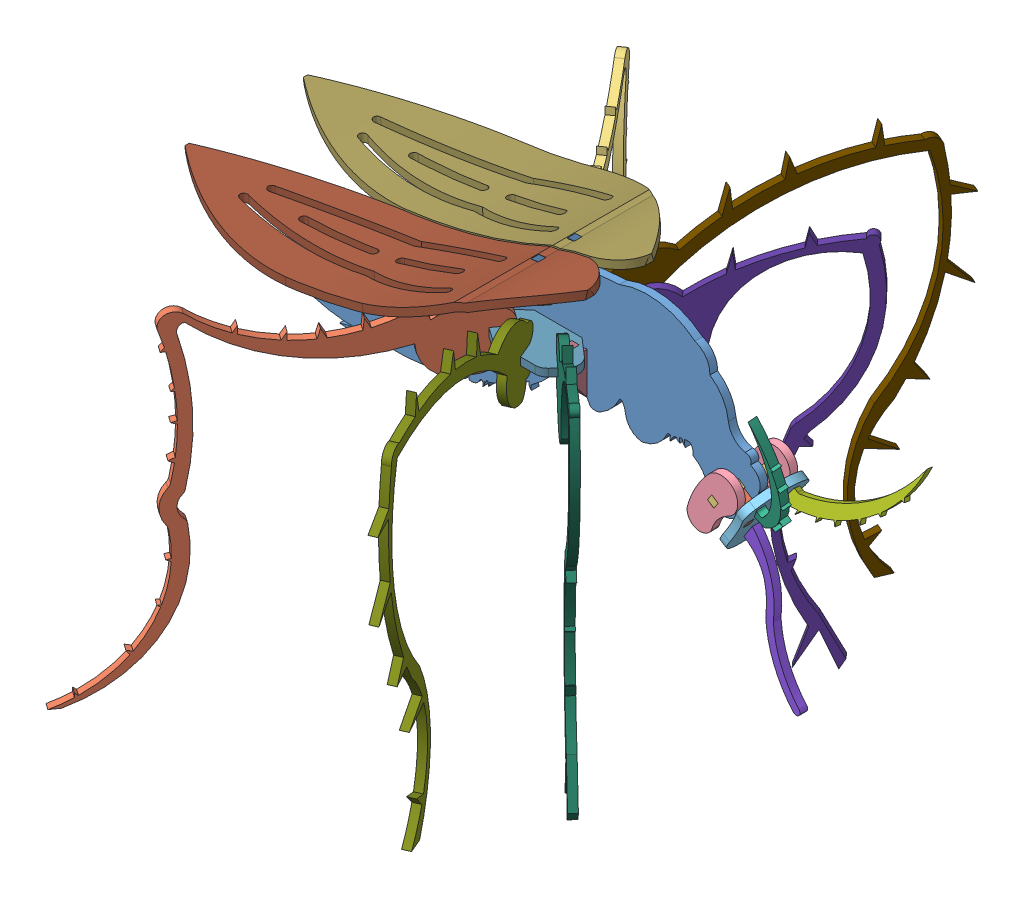
SolidWorks assembly _Assy, Mosquito Rev 0, configuration Default. Lengths in mm.
Overall size (127.53 78.08 120.97).
24 component instances, 21 part files, 68 mates.
Components (placement in the parent):
- Mosquito, Profile-1: Mosquito, Profile [Default] at (-40.9483 -56.761 -14.7323) size (93.14 36.88 1.52)
- Mosquito, Face Plt, Connector-1: Mosquito, Face Plt, Connector [Default] at (15.6801 29.1957 -14.7323) x (0.835069 -0.550145 0) z (0.550145 0.835069 0) size (6.57 8.05 1.52)
- Mosquito, Eye Plt, Connector-1: Mosquito, Eye Plt, Connector [Default] at (62.8149 -1.8568 -14.7323) x (0.550145 0.835069 0) z (-0.835069 0.550145 0) size (2.82 5.2 1.52)
- Mosquito, Eye Plt, Connector-2: Mosquito, Eye Plt, Connector [Default] at (61.5423 -1.0184 -13.2083) x (0.550145 0.835069 0) z (0.835069 -0.550145 0) size (2.82 5.2 1.52)
- Mosquito, Eye-1: Mosquito, Eye [Default] at (61.5423 -1.0184 -9.5093) x (0.550145 0.835069 0) z (0 0 1) size (13.17 6.9 1.52)
- Mosquito, Eye-2: Mosquito, Eye [Default] at (61.5423 -1.0184 -19.9552) x (0.550145 0.835069 0) z (0 0 1) size (13.17 6.9 1.52)
- Mosquito, Face-1: Mosquito, Face [Default] at (66.6075 -4.3553 -14.7323) x (-0.550145 -0.835069 0) z (0.835069 -0.550145 0) size (16.76 12.6 1.52)
- Mosquito, Face Antenna - 01-1: Mosquito, Face Antenna - 01 [Default] at (66.3759 -4.7068 -13.6923) x (0.509952 0.774061 0.375204) z (-0.206417 -0.313322 0.926942) size (30.63 11.64 1.52)
- Mosquito, Face Antenna - 02-1: Mosquito, Face Antenna - 02 [Default] at (66.6675 -4.2642 -14.4628) x (-0.509952 -0.774061 0.375204) z (-0.206417 -0.313322 -0.926942) size (22.51 13.81 1.52)
- Mosquito, Face, Biter-1: Mosquito, Face, Biter [Default] at (66.6075 -4.3553 -13.2083) x (-0.550145 -0.835069 0) z (0 0 -1) size (18.96 24.73 1.52)
- Mosquito, Wing Plt, Connector-1: Mosquito, Wing Plt, Connector [Default] at (-47.8002 6.962 -14.7323) x (0.994269 0.106911 0) z (-0.106911 0.994269 0) size (9.72 13.37 1.52)
- Mosquito, Wing Plt-1: Mosquito, Wing Plt [Default] at (-47.8002 6.962 -11.1106) x (-0.994269 -0.106911 0) z (0 0 1) size (6.76 6.62 1.52)
- Mosquito, Wing Plt-2: Mosquito, Wing Plt [Default] at (-47.8002 6.962 -18.3539) x (-0.994269 -0.106911 0) z (0 0 1) size (6.76 6.62 1.52)
- Mosquito, Wing-1: Mosquito, Wing [Default] at (-47.8002 6.962 -9.5866) x (-0.994269 -0.106911 0) z (0 0 1) size (75.96 9.36 29.29)
- MirrorMosquito, Wing-2: MirrorMosquito, Wing [Default] at (-47.8002 6.962 -18.3539) x (-0.994269 -0.106911 0) z (0 0 1) size (75.96 9.36 29.29)
- Mosquito, Leg Plt, Connector-1: Mosquito, Leg Plt, Connector [Default] at (32.2496 -56.761 -14.7323) x (0 0 1) z (-1 0 0) size (13.29 9.8 1.52)
- Mosquito, Leg Plt, Base-1: Mosquito, Leg Plt, Base [Default] at (32.2496 7.7234 -14.7323) x (0 0 1) z (0 1 0) size (9.45 17.8 1.52)
- Mosquito, Leg, Front-1: Mosquito, Leg, Front [Default] at (29.5385 7.7234 -11.7482) x (0 -1 0) z (-0.672441 0 0.740151) size (75.29 39.25 1.52)
- Mosquito, Leg, Middle-1: Mosquito, Leg, Middle [Default] at (24.4896 7.7234 -13.0681) x (-0.39243 0 -0.919782) z (-0.919782 0 0.39243) size (58.76 78.08 1.52)
- MirrorMosquito, Leg, Front-2: MirrorMosquito, Leg, Front [Default] at (29.5385 7.7234 -16.1923) x (0 -1 0) z (0.672441 0 0.740151) size (75.29 39.25 1.52)
- MirrorPart4^_Assy, Mosquito Rev 0-3: MirrorPart4^_Assy, Mosquito Rev 0 [Default] at (24.4896 7.7234 -14.8724) x (-0.39243 0 0.919782) z (0.919782 0 0.39243) size (58.76 78.08 1.52) (virtual)
- MirrorMosquito, Leg Plt, Base-2: MirrorMosquito, Leg Plt, Base [Default] at (32.2496 7.7234 -13.2083) x (0 0 -1) z (0 -1 0) size (9.45 17.8 1.52)
- Mosquito, Leg, Rear-1: Mosquito, Leg, Rear [Default] at (27.2529 7.7234 -18.2575) x (-0.576476 0 0.817114) z (0.817114 0 0.576476) size (67.19 66.57 1.52)
- MirrorMosquito, Leg, Rear-2: MirrorMosquito, Leg, Rear [Default] at (27.2529 7.7234 -9.6831) x (-0.576476 0 -0.817114) z (-0.817114 0 0.576476) size (67.19 66.57 1.52)
Mates (geometry in assembly coordinates):
- InPlace2: in place: plane of Mosquito, Profile-1 through (15.6801 29.1957 -14.7323) normal (0.550145 0.835069 0); plane of ? through (18.1585 27.5629 0) normal (0.550145 0.835069 0); moOrthogonalPlaneRef_w of Mosquito, Profile-1 through (15.6801 29.1957 -14.7323) normal (0.550145 0.835069 0); unknown of ?; plane of Mosquito, Profile-1 through (15.6801 29.1957 -14.7323) normal (0.550145 0.835069 0); line of ? through (-55 18.1585 27.5629) axis (0 0.835069 -0.550145); plane of Mosquito, Profile-1 through (15.6801 29.1957 -14.7323) normal (0.550145 0.835069 0); unknown of Mosquito, Face Plt, Connector-1
- Coincident4: coincident aligned: plane of Mosquito, Profile-1; plane of Mosquito, Face Plt, Connector-1
- Coincident5: coincident aligned: moOrthogonalPlaneRef_w of Mosquito, Profile-1 through (15.6801 29.1957 -14.7323) normal (0 0 -1); plane of Mosquito, Face Plt, Connector-1
- Coincident6: coincident anti-aligned: moOrthogonalPlaneRef_w of Mosquito, Profile-1 through (15.6801 29.1957 -14.7323) normal (-0.835069 0.550145 0); plane of Mosquito, Face Plt, Connector-1
- InPlace3: in place: plane of Mosquito, Face Plt, Connector-1 through (62.8149 -1.8568 -15.0636) normal (-0.835069 0.550145 0); plane of ? through (44.6564 -29.4197 0) normal (-0.835069 0.550145 0); plane of Mosquito, Face Plt, Connector-1 through (62.8149 -1.8568 -15.0636) normal (-0.835069 0.550145 0); line of ? through (-55 44.6564 -29.4197) axis (0 0.550145 0.835069); plane of Mosquito, Face Plt, Connector-1 through (62.8149 -1.8568 -15.0636) normal (-0.835069 0.550145 0); unknown of ?; plane of Mosquito, Face Plt, Connector-1 through (62.8149 -1.8568 -15.0636) normal (-0.835069 0.550145 0); unknown of Mosquito, Eye Plt, Connector-1
- Coincident7: coincident aligned: plane of Mosquito, Face Plt, Connector-1; plane of Mosquito, Eye Plt, Connector-1
- Coincident8: coincident aligned: moOrthogonalPlaneRef_w of Mosquito, Face Plt, Connector-1 through (62.8149 -1.8568 -14.7323) normal (0 0 -1); plane of Mosquito, Eye Plt, Connector-1
- Coincident9: coincident anti-aligned: moOrthogonalPlaneRef_w of Mosquito, Face Plt, Connector-1 through (62.8149 -1.8568 -14.7323) normal (-0.550145 -0.835069 0); plane of Mosquito, Eye Plt, Connector-1
- Coincident10: coincident anti-aligned: plane of Mosquito, Face Plt, Connector-1 through (15.6801 29.1957 -12.8769) normal (0 0 1); plane of Mosquito, Eye Plt, Connector-2 through (62.8149 -1.8568 -12.8769) normal (0 0 -1)
- Coincident11: coincident anti-aligned: plane of Mosquito, Face Plt, Connector-1 through (62.8149 -1.8568 -12.8769) normal (-0.835069 0.550145 0); plane of Mosquito, Eye Plt, Connector-2 through (62.8149 -1.8568 -13.2083) normal (0.835069 -0.550145 0)
- Coincident12: coincident anti-aligned: plane of Mosquito, Face Plt, Connector-1 through (15.6801 29.1957 -14.7323) normal (-0.550145 -0.835069 0); plane of Mosquito, Eye Plt, Connector-2 through (62.8149 -1.8568 -13.2083) normal (0.550145 0.835069 0)
- InPlace4: in place: plane of Mosquito, Eye Plt, Connector-2 through (62.8149 -1.8568 -9.5093) normal (0 0 1); plane of ? through (0 0 -9.5093) normal (0 0 1); plane of Mosquito, Eye Plt, Connector-2 through (62.8149 -1.8568 -9.5093) normal (0 0 1); plane of ? through (0 0 -9.5093) normal (0 1 0); plane of Mosquito, Eye Plt, Connector-2 through (62.8149 -1.8568 -9.5093) normal (0 0 1); plane of ? through (0 0 -9.5093) normal (1 0 0); plane of Mosquito, Eye Plt, Connector-2 through (62.8149 -1.8568 -9.5093) normal (0 0 1); unknown of Mosquito, Eye-1
- Coincident13: coincident aligned: plane of Mosquito, Eye Plt, Connector-2; plane of Mosquito, Eye-1
- Coincident14: coincident aligned: moOrthogonalPlaneRef_w of Mosquito, Eye Plt, Connector-2 through (61.5423 -1.0184 -9.5093) normal (-0.835069 0.550145 0); plane of Mosquito, Eye-1
- Coincident15: coincident anti-aligned: moOrthogonalPlaneRef_w of Mosquito, Eye Plt, Connector-2 through (61.5423 -1.0184 -9.5093) normal (-0.550145 -0.835069 0); plane of Mosquito, Eye-1
- Coincident16: coincident anti-aligned: plane of Mosquito, Eye Plt, Connector-1 through (61.5423 -1.0184 -18.4312) normal (0 0 -1); plane of Mosquito, Eye-2 through (66.3052 -3.0819 -18.4312) normal (0 0 1)
- Coincident17: coincident anti-aligned: plane of Mosquito, Eye Plt, Connector-1 through (61.5423 -1.0184 -14.7323) normal (-0.550145 -0.835069 0); plane of Mosquito, Eye-2 through (62.8149 -1.8568 -18.4312) normal (0.550145 0.835069 0)
- Coincident18: coincident anti-aligned: plane of Mosquito, Eye Plt, Connector-1 through (62.8149 -1.8568 -14.7323) normal (0.835069 -0.550145 0); plane of Mosquito, Eye-2 through (63.6534 -0.5841 -18.4312) normal (-0.835069 0.550145 0)
- InPlace5: in place: plane of Mosquito, Face Plt, Connector-1 through (67.4459 -3.0826 -9.9445) normal (0.835069 -0.550145 0); plane of ? through (48.449 -31.9182 0) normal (0.835069 -0.550145 0); plane of Mosquito, Face Plt, Connector-1 through (67.4459 -3.0826 -9.9445) normal (0.835069 -0.550145 0); line of ? through (-55 48.449 -31.9182) axis (0 0.550145 0.835069); plane of Mosquito, Face Plt, Connector-1 through (67.4459 -3.0826 -9.9445) normal (0.835069 -0.550145 0); unknown of ?; plane of Mosquito, Face Plt, Connector-1 through (67.4459 -3.0826 -9.9445) normal (0.835069 -0.550145 0); unknown of Mosquito, Face-1
- Coincident19: coincident aligned: plane of Mosquito, Face Plt, Connector-1; plane of Mosquito, Face-1
- Coincident20: coincident aligned: moOrthogonalPlaneRef_w of Mosquito, Face Plt, Connector-1 through (66.6075 -4.3553 -14.7323) normal (0 0 -1); plane of Mosquito, Face-1
- Coincident21: coincident anti-aligned: moOrthogonalPlaneRef_w of Mosquito, Face Plt, Connector-1 through (66.6075 -4.3553 -14.7323) normal (0.550145 0.835069 0); plane of Mosquito, Face-1
- InPlace6: in place: plane of Mosquito, Face-1 through (67.6068 -0.0682 -11.8502) normal (-0.206417 -0.313322 0.926942); plane of ? through (5.1435 7.8074 -23.0978) normal (-0.206417 -0.313322 0.926942); plane of Mosquito, Face-1 through (67.6068 -0.0682 -11.8502) normal (-0.206417 -0.313322 0.926942); unknown of ?; plane of Mosquito, Face-1 through (67.6068 -0.0682 -11.8502) normal (-0.206417 -0.313322 0.926942); unknown of ?; plane of Mosquito, Face-1 through (67.6068 -0.0682 -11.8502) normal (-0.206417 -0.313322 0.926942); unknown of Mosquito, Face Antenna - 01-1
- Coincident22: coincident aligned: plane of Mosquito, Face-1; plane of Mosquito, Face Antenna - 01-1
- Coincident23: coincident aligned: moOrthogonalPlaneRef_w of Mosquito, Face-1 through (66.3759 -4.7068 -13.6923) normal (-0.835069 0.550145 0); plane of Mosquito, Face Antenna - 01-1
- Coincident24: coincident anti-aligned: moOrthogonalPlaneRef_w of Mosquito, Face-1 through (66.3759 -4.7068 -13.6923) normal (-0.509952 -0.774061 -0.375204); plane of Mosquito, Face Antenna - 01-1
- InPlace7: in place: plane of Mosquito, Face-1 through (67.6068 -0.0682 -16.0903) normal (-0.206417 -0.313322 -0.926942); plane of ? through (-0.2025 -0.3074 -0.9093) normal (-0.206417 -0.313322 -0.926942); plane of Mosquito, Face-1 through (67.6068 -0.0682 -16.0903) normal (-0.206417 -0.313322 -0.926942); unknown of ?; plane of Mosquito, Face-1 through (67.6068 -0.0682 -16.0903) normal (-0.206417 -0.313322 -0.926942); unknown of ?; plane of Mosquito, Face-1 through (67.6068 -0.0682 -16.0903) normal (-0.206417 -0.313322 -0.926942); unknown of Mosquito, Face Antenna - 02-1
- Coincident25: coincident aligned: plane of Mosquito, Face-1; plane of Mosquito, Face Antenna - 02-1
- Coincident26: coincident aligned: moOrthogonalPlaneRef_w of Mosquito, Face-1 through (66.6675 -4.2642 -14.4628) normal (-0.835069 0.550145 0); plane of Mosquito, Face Antenna - 02-1
- Coincident27: coincident anti-aligned: moOrthogonalPlaneRef_w of Mosquito, Face-1 through (66.6675 -4.2642 -14.4628) normal (0.509952 0.774061 -0.375204); plane of Mosquito, Face Antenna - 02-1
- InPlace8: in place: plane of Mosquito, Face-1 through (63.5713 -6.1937 -13.2083) normal (0 0 -1); plane of ? through (0 0 -13.2083) normal (0 0 -1); plane of Mosquito, Face-1 through (63.5713 -6.1937 -13.2083) normal (0 0 -1); unknown of ?; plane of Mosquito, Face-1 through (63.5713 -6.1937 -13.2083) normal (0 0 -1); plane of ? through (0 0 -13.2083) normal (-1 0 0); plane of Mosquito, Face-1 through (63.5713 -6.1937 -13.2083) normal (0 0 -1); unknown of Mosquito, Face, Biter-1
- Coincident28: coincident aligned: plane of Mosquito, Face-1; plane of Mosquito, Face, Biter-1
- Coincident29: coincident aligned: moOrthogonalPlaneRef_w of Mosquito, Face-1 through (66.6075 -4.3553 -13.2083) normal (-0.835069 0.550145 0); plane of Mosquito, Face, Biter-1
- Coincident30: coincident anti-aligned: moOrthogonalPlaneRef_w of Mosquito, Face-1 through (66.6075 -4.3553 -13.2083) normal (0.550145 0.835069 0); plane of Mosquito, Face, Biter-1
- InPlace9: in place: plane of Mosquito, Profile-1 through (11.8017 13.3708 -13.2083) normal (-0.106911 0.994269 0); plane of ? through (-1.2864 11.9635 0) normal (-0.106911 0.994269 0); plane of Mosquito, Profile-1 through (11.8017 13.3708 -13.2083) normal (-0.106911 0.994269 0); unknown of ?; plane of Mosquito, Profile-1 through (11.8017 13.3708 -13.2083) normal (-0.106911 0.994269 0); line of ? through (-55 -1.2864 11.9635) axis (0 0.994269 0.106911); plane of Mosquito, Profile-1 through (11.8017 13.3708 -13.2083) normal (-0.106911 0.994269 0); unknown of Mosquito, Wing Plt, Connector-1
- Coincident31: coincident aligned: plane of Mosquito, Profile-1; plane of Mosquito, Wing Plt, Connector-1
- Coincident32: coincident aligned: moOrthogonalPlaneRef_w of Mosquito, Profile-1 through (-47.8002 6.962 -14.7323) normal (0 0 -1); plane of Mosquito, Wing Plt, Connector-1
- Coincident33: coincident anti-aligned: moOrthogonalPlaneRef_w of Mosquito, Profile-1 through (-47.8002 6.962 -14.7323) normal (-0.994269 -0.106911 0); plane of Mosquito, Wing Plt, Connector-1
- InPlace10: in place: plane of Mosquito, Wing Plt, Connector-1 through (26.7529 16.5112 -11.1106) normal (0 0 1); plane of ? through (0 0 -11.1106) normal (0 0 1); plane of Mosquito, Wing Plt, Connector-1 through (26.7529 16.5112 -11.1106) normal (0 0 1); plane of ? through (0 0 -11.1106) normal (0 1 0); plane of Mosquito, Wing Plt, Connector-1 through (26.7529 16.5112 -11.1106) normal (0 0 1); plane of ? through (0 0 -11.1106) normal (1 0 0); plane of Mosquito, Wing Plt, Connector-1 through (26.7529 16.5112 -11.1106) normal (0 0 1); unknown of Mosquito, Wing Plt-1
- Coincident34: coincident aligned: plane of Mosquito, Wing Plt, Connector-1; plane of Mosquito, Wing Plt-1
- Coincident35: coincident aligned: moOrthogonalPlaneRef_w of Mosquito, Wing Plt, Connector-1 through (-47.8002 6.962 -11.1106) normal (0.106911 -0.994269 0); plane of Mosquito, Wing Plt-1
- Coincident36: coincident anti-aligned: moOrthogonalPlaneRef_w of Mosquito, Wing Plt, Connector-1 through (-47.8002 6.962 -11.1106) normal (0.994269 0.106911 0); plane of Mosquito, Wing Plt-1
- Coincident37: coincident anti-aligned: plane of Mosquito, Wing Plt, Connector-1 through (23.7224 16.1854 -18.3539) normal (0.994269 0.106911 0); plane of Mosquito, Wing Plt-2 through (23.8853 14.6701 -16.8299) normal (-0.994269 -0.106911 0)
- Coincident38: coincident anti-aligned: plane of Mosquito, Wing Plt, Connector-1 through (26.7529 16.5112 -16.8299) normal (0 0 -1); plane of ? through (-47.8002 6.962 -16.8299) normal (0 0 1)
- Coincident39: coincident aligned: plane of Mosquito, Wing Plt, Connector-1 through (27.6735 15.0774 -17.4026) normal (0.106911 -0.994269 0); plane of ? through (26.9159 14.996 -16.8299) normal (0.106911 -0.994269 0)
- InPlace11: in place: plane of Mosquito, Wing Plt-1 through (-47.8002 6.962 -9.5866) normal (0 0 1); plane of ? through (0 0 -9.5866) normal (0 0 1); plane of Mosquito, Wing Plt-1 through (-47.8002 6.962 -9.5866) normal (0 0 1); plane of ? through (0 0 -9.5866) normal (0 1 0); plane of Mosquito, Wing Plt-1 through (-47.8002 6.962 -9.5866) normal (0 0 1); plane of ? through (0 0 -9.5866) normal (1 0 0); plane of Mosquito, Wing Plt-1 through (-47.8002 6.962 -9.5866) normal (0 0 1); unknown of Mosquito, Wing-1
- Coincident40: coincident aligned: plane of Mosquito, Wing Plt-1; plane of Mosquito, Wing-1
- Coincident41: coincident aligned: moOrthogonalPlaneRef_w of Mosquito, Wing Plt-1 through (-47.8002 6.962 -9.5866) normal (0.106911 -0.994269 0); plane of Mosquito, Wing-1
- Coincident42: coincident anti-aligned: moOrthogonalPlaneRef_w of Mosquito, Wing Plt-1 through (-47.8002 6.962 -9.5866) normal (0.994269 0.106911 0); plane of Mosquito, Wing-1
- InPlace13: in place: plane of Mosquito, Profile-1 through (32.2496 -56.761 -14.7323) normal (-1 0 0); plane of ? through (32.2496 0 0) normal (-1 0 0); plane of Mosquito, Profile-1 through (32.2496 -56.761 -14.7323) normal (-1 0 0); line of ? through (-55 32.2496 0) axis (0 0 1); plane of Mosquito, Profile-1 through (32.2496 -56.761 -14.7323) normal (-1 0 0); plane of ? through (32.2496 0 0) normal (0 0 1); plane of Mosquito, Profile-1 through (32.2496 -56.761 -14.7323) normal (-1 0 0); unknown of Mosquito, Leg Plt, Connector-1
- Coincident46: coincident aligned: plane of Mosquito, Profile-1; plane of Mosquito, Leg Plt, Connector-1
- Coincident47: coincident aligned: moOrthogonalPlaneRef_w of Mosquito, Profile-1 through (32.2496 -56.761 -14.7323) normal (0 1 0); plane of Mosquito, Leg Plt, Connector-1
- Coincident48: coincident anti-aligned: moOrthogonalPlaneRef_w of Mosquito, Profile-1 through (32.2496 -56.761 -14.7323) normal (0 0 -1); plane of Mosquito, Leg Plt, Connector-1 through (32.2496 -56.761 -14.7323) normal (0 0 1)
- InPlace14: in place: plane of Mosquito, Leg Plt, Connector-1 through (30.7256 7.7234 -10.1603) normal (0 1 0); plane of ? through (0 7.7234 0) normal (0 1 0); plane of Mosquito, Leg Plt, Connector-1 through (30.7256 7.7234 -10.1603) normal (0 1 0); plane of ? through (0 7.7234 0) normal (0 0 -1); plane of Mosquito, Leg Plt, Connector-1 through (30.7256 7.7234 -10.1603) normal (0 1 0); line of ? through (-55 0 7.7234) axis (0 1 0); plane of Mosquito, Leg Plt, Connector-1 through (30.7256 7.7234 -10.1603) normal (0 1 0); unknown of Mosquito, Leg Plt, Base-1
- Coincident40: coincident aligned: plane of Mosquito, Leg Plt, Connector-1; plane of Mosquito, Leg Plt, Base-1
- Coincident41: coincident aligned: moOrthogonalPlaneRef_w of Mosquito, Leg Plt, Connector-1 through (32.2496 7.7234 -14.7323) normal (1 0 0); plane of Mosquito, Leg Plt, Base-1
- Coincident42: coincident anti-aligned: moOrthogonalPlaneRef_w of Mosquito, Leg Plt, Connector-1 through (32.2496 7.7234 -14.7323) normal (0 0 -1); plane of Mosquito, Leg Plt, Base-1
- InPlace15: in place: plane of Mosquito, Leg Plt, Base-1 through (35.1206 9.2474 -6.6767) normal (-0.672441 0 0.740151); plane of ? through (19.2038 0 -21.1375) normal (-0.672441 0 0.740151); plane of Mosquito, Leg Plt, Base-1 through (35.1206 9.2474 -6.6767) normal (-0.672441 0 0.740151); unknown of ?; plane of Mosquito, Leg Plt, Base-1 through (35.1206 9.2474 -6.6767) normal (-0.672441 0 0.740151); plane of ? through (19.2038 0 -21.1375) normal (0.740151 0 0.672441); plane of Mosquito, Leg Plt, Base-1 through (35.1206 9.2474 -6.6767) normal (-0.672441 0 0.740151); unknown of Mosquito, Leg, Front-1
- Coincident43: coincident aligned: plane of Mosquito, Leg Plt, Base-1; plane of Mosquito, Leg, Front-1
- Coincident44: coincident aligned: moOrthogonalPlaneRef_w of Mosquito, Leg Plt, Base-1 through (29.5385 7.7234 -11.7482) normal (0.740151 0 0.672441); plane of Mosquito, Leg, Front-1
- Coincident45: coincident anti-aligned: moOrthogonalPlaneRef_w of Mosquito, Leg Plt, Base-1 through (29.5385 7.7234 -11.7482) normal (0 1 0); plane of Mosquito, Leg, Front-1
- Coincident49: coincident anti-aligned: plane of Mosquito, Leg Plt, Base-1 through (28.4598 9.2474 -3.7627) normal (-0.919782 0 0.39243); plane of Mosquito, Leg, Middle-1 through (24.4896 7.7234 -13.0681) normal (0.919782 0 -0.39243)
- Coincident50: coincident anti-aligned: plane of Mosquito, Leg Plt, Base-1 through (32.2496 9.2474 -14.7323) normal (0 1 0); plane of Mosquito, Leg, Middle-1 through (23.0878 9.2474 -12.4701) normal (0 -1 0)
- Coincident51: coincident anti-aligned: plane of Mosquito, Leg Plt, Base-1 through (27.6998 9.2474 -5.5441) normal (0.39243 0 0.919782); plane of Mosquito, Leg, Middle-1 through (26.298 7.7234 -4.946) normal (-0.39243 0 -0.919782)
- InPlace17: in place: plane of Mosquito, Leg Plt, Base-1 through (18.9946 9.2474 -6.552) normal (0.817114 0 0.576476); plane of ? through (9.5959 0 6.77) normal (0.817114 0 0.576476); plane of Mosquito, Leg Plt, Base-1 through (18.9946 9.2474 -6.552) normal (0.817114 0 0.576476); unknown of ?; plane of Mosquito, Leg Plt, Base-1 through (18.9946 9.2474 -6.552) normal (0.817114 0 0.576476); plane of ? through (9.5959 0 6.77) normal (0.576476 0 -0.817114); plane of Mosquito, Leg Plt, Base-1 through (18.9946 9.2474 -6.552) normal (0.817114 0 0.576476); unknown of Mosquito, Leg, Rear-1
- Coincident52: coincident aligned: plane of Mosquito, Leg Plt, Base-1; plane of ?
- Coincident53: coincident aligned: moOrthogonalPlaneRef_w of Mosquito, Leg Plt, Base-1 through (27.2529 7.7234 -18.2575) normal (0 -1 0); plane of Mosquito, Leg, Rear-1
- Coincident54: coincident anti-aligned: moOrthogonalPlaneRef_w of Mosquito, Leg Plt, Base-1 through (27.2529 7.7234 -18.2575) normal (0.576476 0 -0.817114); plane of Mosquito, Leg, Rear-1
